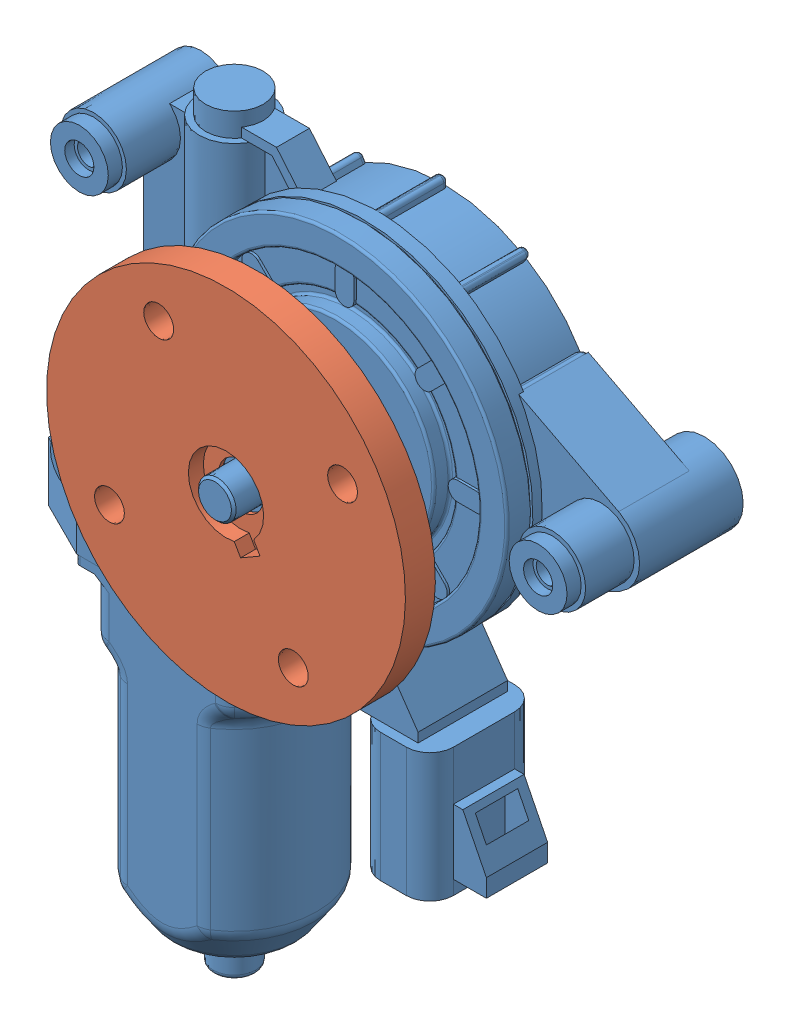
SolidWorks assembly Window Motor Right with adapter, configuration Default. Lengths in mm.
Overall size (120.53 173.05 55.5).
2 component instances, 2 part files, 0 mates.
Components (placement in the parent):
- ND Motor Right-1: ND Motor Right [Default] at origin size (120.53 161 55.5)
- nippondensogearcoupler2-1: nippondensogearcoupler2 [Default] at (0 0 25.489) x (-0.866025 -0.5 0) z (0 0 -1) size (76.2 76.2 19.05)
